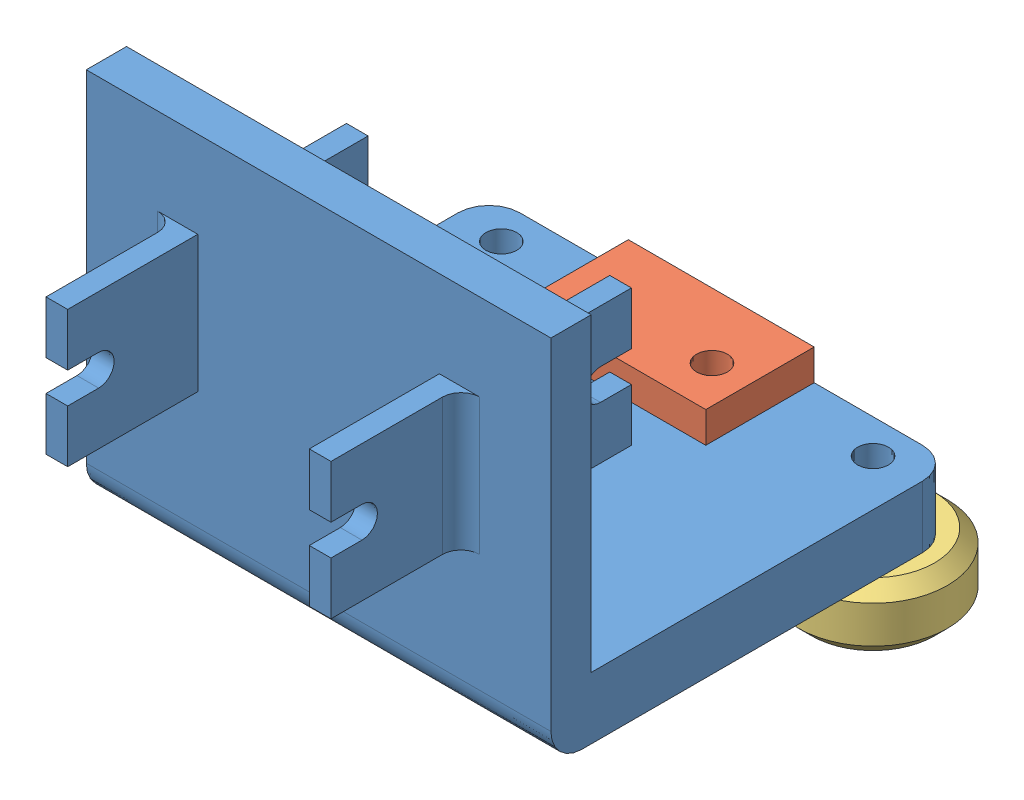
SolidWorks assembly laser_mount_assem, configuration Default. Lengths in mm.
Overall size (79.5 80 92.5).
3 component instances, 3 part files, 4 mates.
Components (placement in the parent):
- centre_laser_mount-1: centre_laser_mount [Default] at origin size (75 60 86)
- timing_belt_bracket-1: timing_belt_bracket [Default] at (15 -20 -22.5) x (-1 0 0) z (0 0 -1) size (30 35 17.5)
- V_Slot_Wheel_OD24xID5-1: V_Slot_Wheel_OD24xID5 [Default] at (30 -5.1 -22) x (1 0 0) z (0 -1 0) size (24 24 10.2)
Mates (geometry in assembly coordinates):
- Coincident1: coincident anti-aligned: plane of centre_laser_mount-1 through (0 10 0) normal (0 1 0); plane of timing_belt_bracket-1 through (-15 10 -3.5) normal (0 -1 0)
- Coincident2: coincident anti-aligned: plane of centre_laser_mount-1 through (0 0 -22.5) normal (0 0 -1); plane of timing_belt_bracket-1 through (15 -20 -22.5) normal (0 0 1)
- Coincident3: coincident anti-aligned: plane of centre_laser_mount-1 through (15 -20 -22.5) normal (-1 0 0); plane of timing_belt_bracket-1 through (15 10 -27.5) normal (1 0 0)
- Coincident4: coincident anti-aligned: circle of centre_laser_mount-1; circle of V_Slot_Wheel_OD24xID5-1
